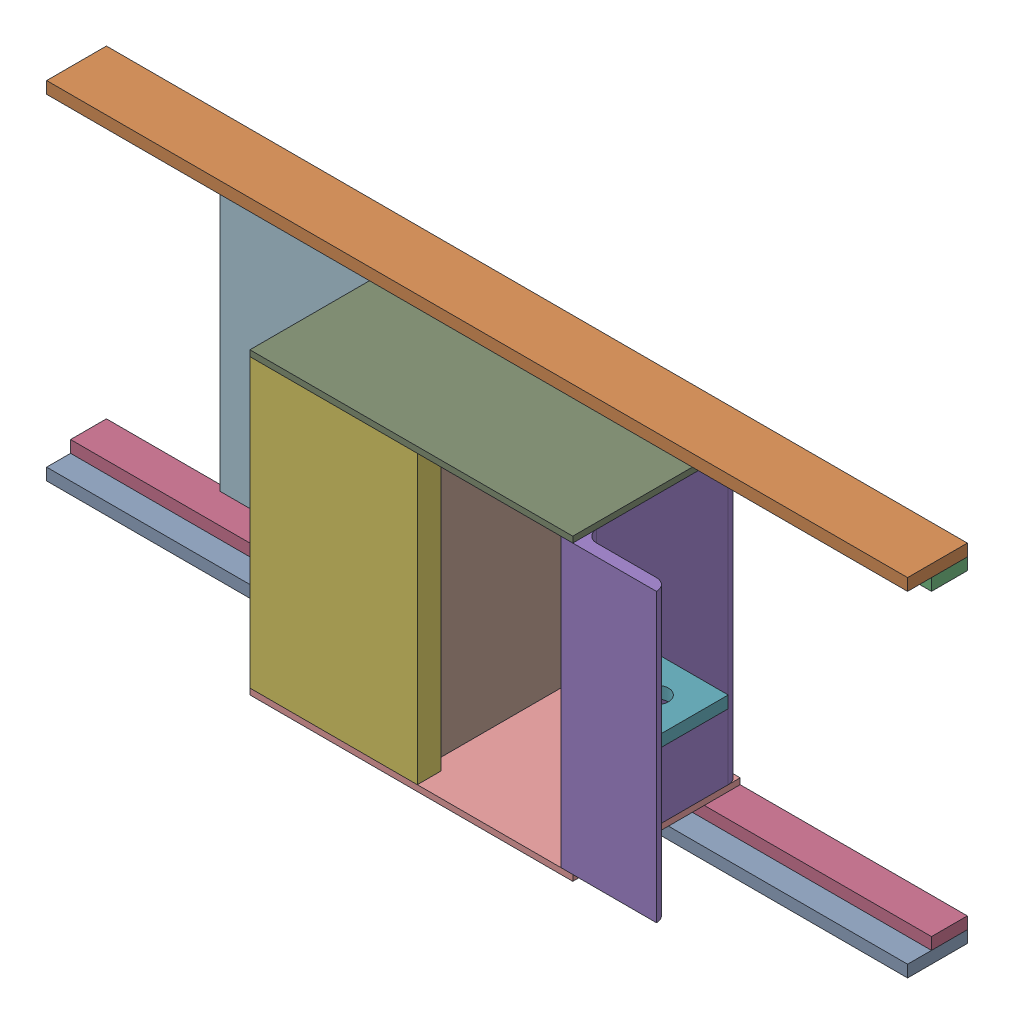
SolidWorks assembly 01-026-00-0, configuration Default. Lengths in mm.
Overall size (914.4 368.3 177.8).
12 component instances, 9 part files, 0 mates.
Components (placement in the parent):
- 01-022-00-0-1: 01-022-00-0 [Default] at (0 -355.6 0) size (914.4 12.7 63.5)
- 01-022-00-0-2: 01-022-00-0 [Default] at origin size (914.4 12.7 63.5)
- 01-023-00-0-1: 01-023-00-0 [Default] at (0 -12.7 -25.4) size (914.4 12.7 38.1)
- 01-023-00-0-2: 01-023-00-0 [Default] at (0 -342.9 -25.4) size (914.4 12.7 38.1)
- 01-024-00-0-1: 01-024-00-0 [Default] at (660.4 -171.45 114.3) x (1 0 0) z (0 1 0) size (101.6 177.8 304.8)
- 01-025-00-0-1: 01-025-00-0 [Default] at (508 -323.85 88.9) x (0 1 0) z (1 0 0) size (304.8 25.4 177.8)
- 01-028-00-0-1: 01-028-00-0 [Default] at (673.1 -165.1 25.4) x (0 0 -1) z (0 -1 0) size (76.2 76.2 12.7)
- 01-029-00-0-1: 01-029-00-0 [Default] at (482.6 -323.85 88.9) x (0 1 0) z (1 0 0) size (304.8 152.4 12.7)
- 01-030-00-0-1: 01-030-00-0 [Default] at (349.25 -19.05 88.9) x (0 0 -1) z (0 1 0) size (177.8 342.9 6.35)
- 01-030-00-0-2: 01-030-00-0 [Default] at (654.05 -323.85 88.9) x (0 0 -1) z (0 -1 0) size (177.8 342.9 6.35)
- 01-031-00-0-1: 01-031-00-0 [Default] at (406.4 -171.45 12.7) x (1 0 0) z (0 0 -1) size (152.4 304.8 152.4)
- 01-032-00-0-1: 01-032-00-0 [Default] at (127 -330.2 -57.15) x (-1 0 0) z (0 0 -1) size (203.2 317.5 6.35)
